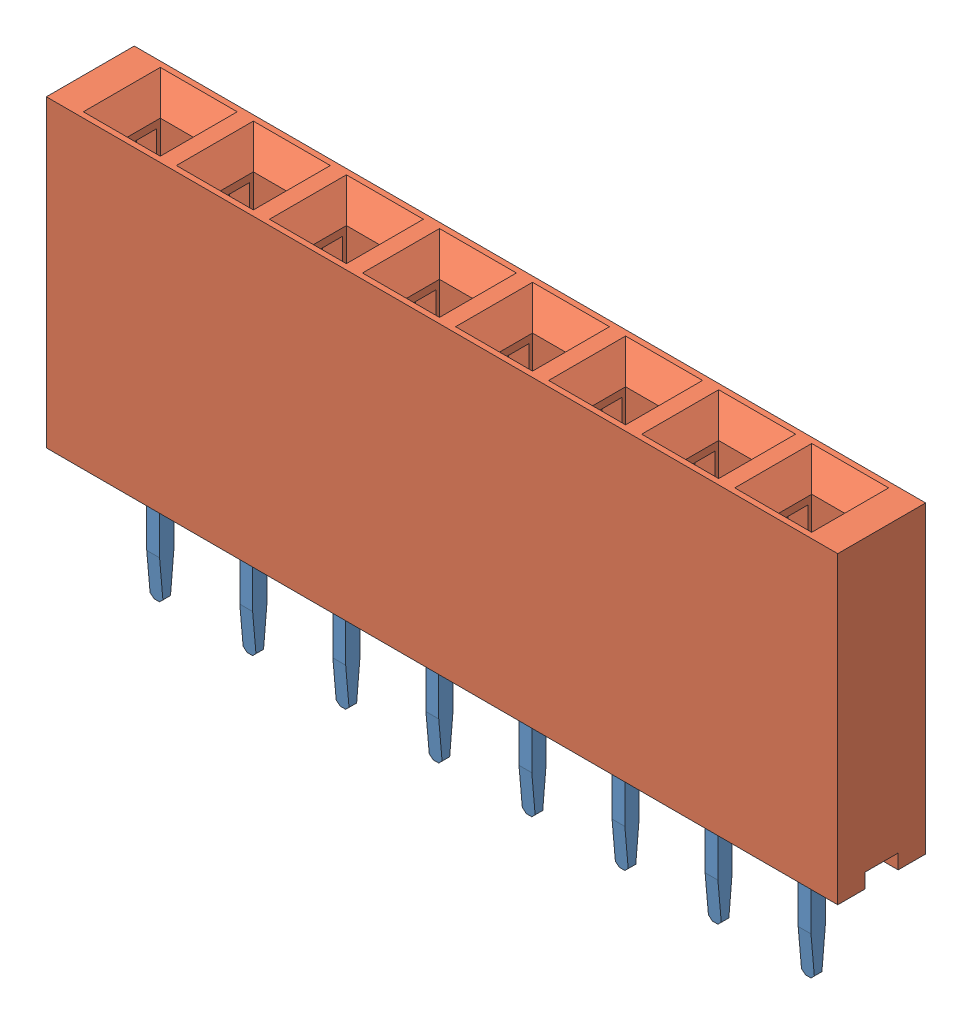
SolidWorks assembly 2_54_x_8_pitch_connector_, configuration Default. Lengths in mm.
Overall size (21.6 11.5 2.4).
2 component instances, 2 part files, 8 mates.
Components (placement in the parent):
- Pitch_x_8-1: Pitch_x_8 [Default] at origin size (19.73 8.86 0.39)
- Plastic_x_8-1: Plastic_x_8 [Default] x (1 0 0) z (0 1 0) size (21.6 2.4 8.3)
Mates (geometry in assembly coordinates):
- На месте1: in place: plane of Pitch_x_8-1 through (0 0 0) normal (0 0 1); moOrthogonalPlaneRef_w of Pitch_x_8-1 through (0 0 0) normal (0 1 0); plane of Pitch_x_8-1 through (0 0 0) normal (1 0 0); unknown of Pitch_x_8-1
- Совпадение1: coincident aligned: 
- Совпадение2: coincident aligned: plane of Pitch_x_8-1 through (0 0 0) normal (0 1 0)
- Совпадение3: coincident anti-aligned: plane of Pitch_x_8-1 through (0 0 0) normal (1 0 0)
- На месте2: in place: plane of Plastic_x_8-1 through (0 0 0) normal (0 1 0); plane of Plastic_x_8-1 through (0 0 0) normal (0 0 -1); plane of Plastic_x_8-1 through (0 0 0) normal (1 0 0); unknown of Plastic_x_8-1
- Совпадение4: coincident aligned: 
- Совпадение5: coincident aligned: plane of Plastic-1 through (0 0 0) normal (0 0 -1)
- Совпадение6: coincident anti-aligned: plane of Plastic-1 through (0 0 0) normal (1 0 0)
